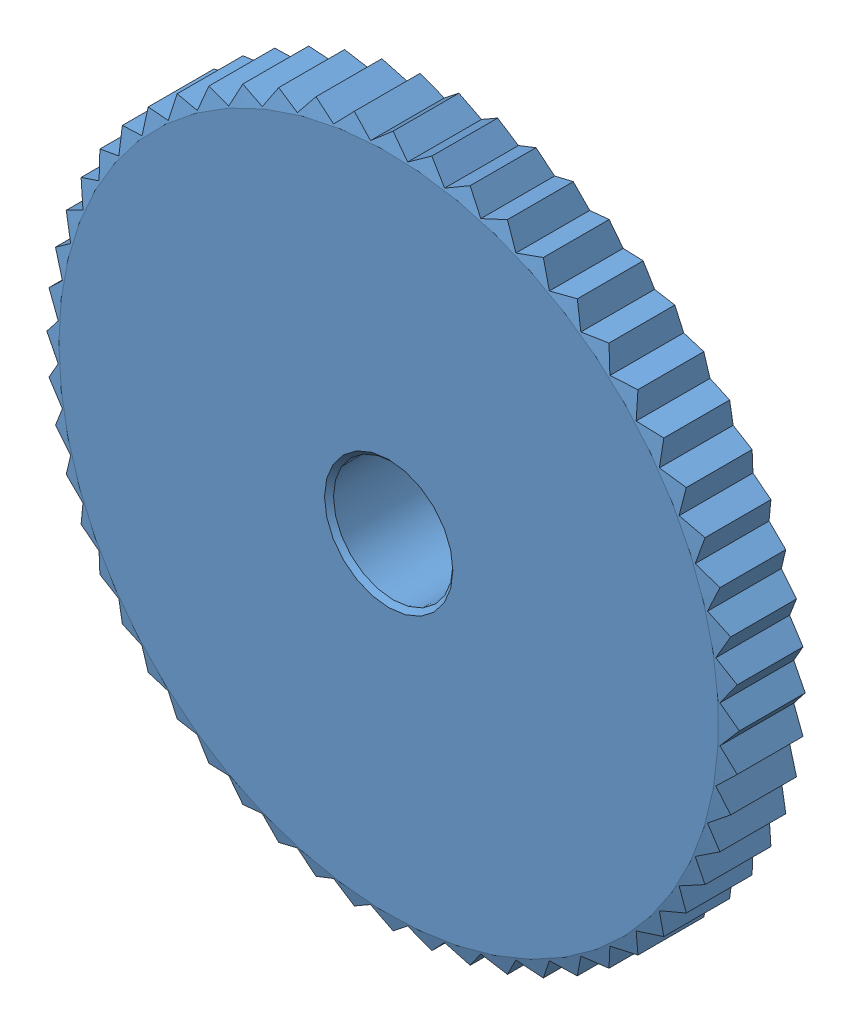
SolidWorks assembly GEABP0_8_56_5_B_8, configuration Default. Lengths in mm.
Overall size (46.4 46.4 14).
2 component instances, 2 part files, 0 mates.
Components (placement in the parent):
- GEABP0_8_56_5_B_8_b-1: GEABP0_8_56_5_B_8_b [Default] x (-1 0 0) z (0 0 -1) size (46.4 46.4 14)
- Hexagon_socket_set_screw_with_flat_point_DIN_913___M4x3-1: Hexagon_socket_set_screw_with_flat_point_DIN_913___M4x3 [Default] at (0 7 -10) x (0 -1 0) z (1 0 0) size (3 4 4)
